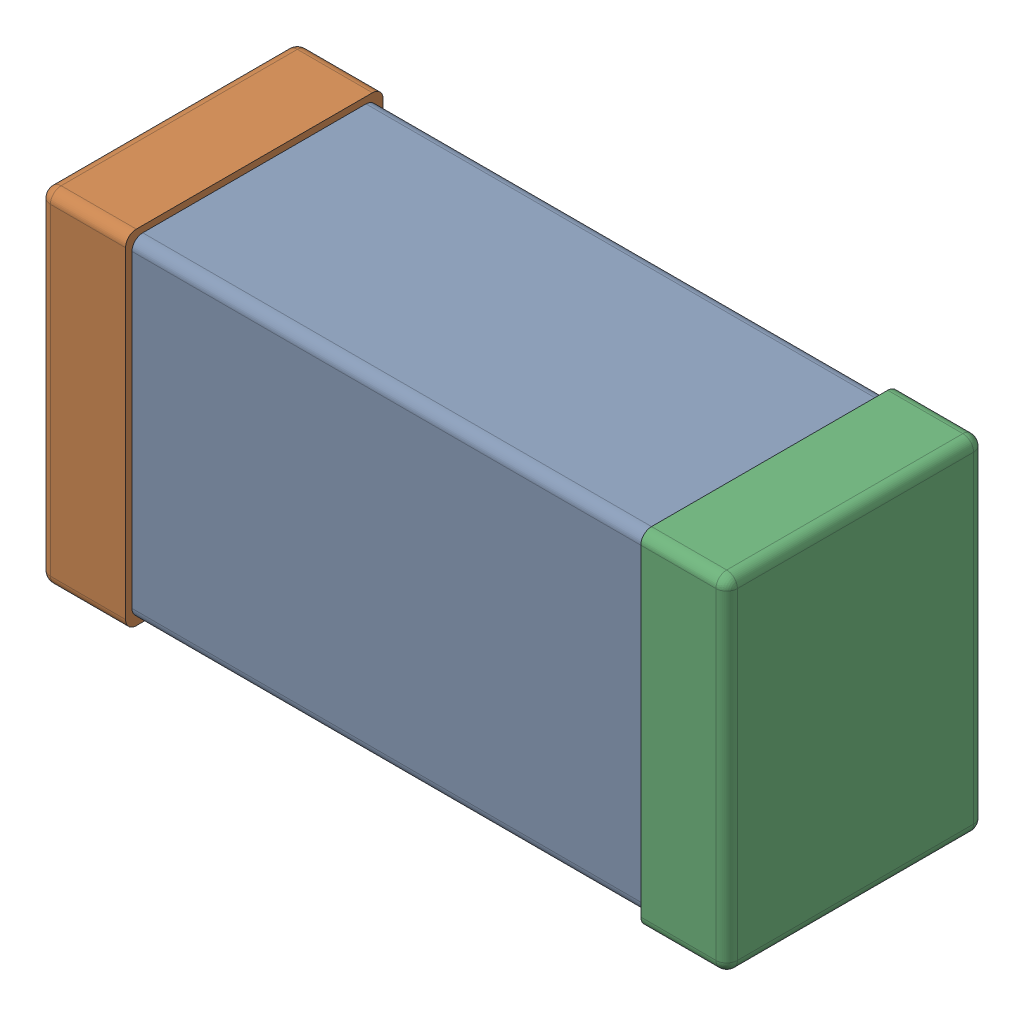
SolidWorks assembly Open CASCADE STEP translator 6.8 48.4, configuration 默认. Lengths in mm.
Overall size (1.6 0.8 0.6).
3 component instances, 3 part files, 0 mates.
Components (placement in the parent):
- C0603_060-1: C0603_060 [默认] at (19.5714 76.962 0) x (-1 0 0) z (0 0 1) size (1.4 0.77 0.57)
- C0603_060_2-1: C0603_060_2 [默认] at (19.5714 76.962 0) x (-1 0 0) z (0 0 1) size (0.2 0.8 0.6)
- C0603_060_3-1: C0603_060_3 [默认] at (19.5714 76.962 0) x (-1 0 0) z (0 0 1) size (0.2 0.8 0.6)
